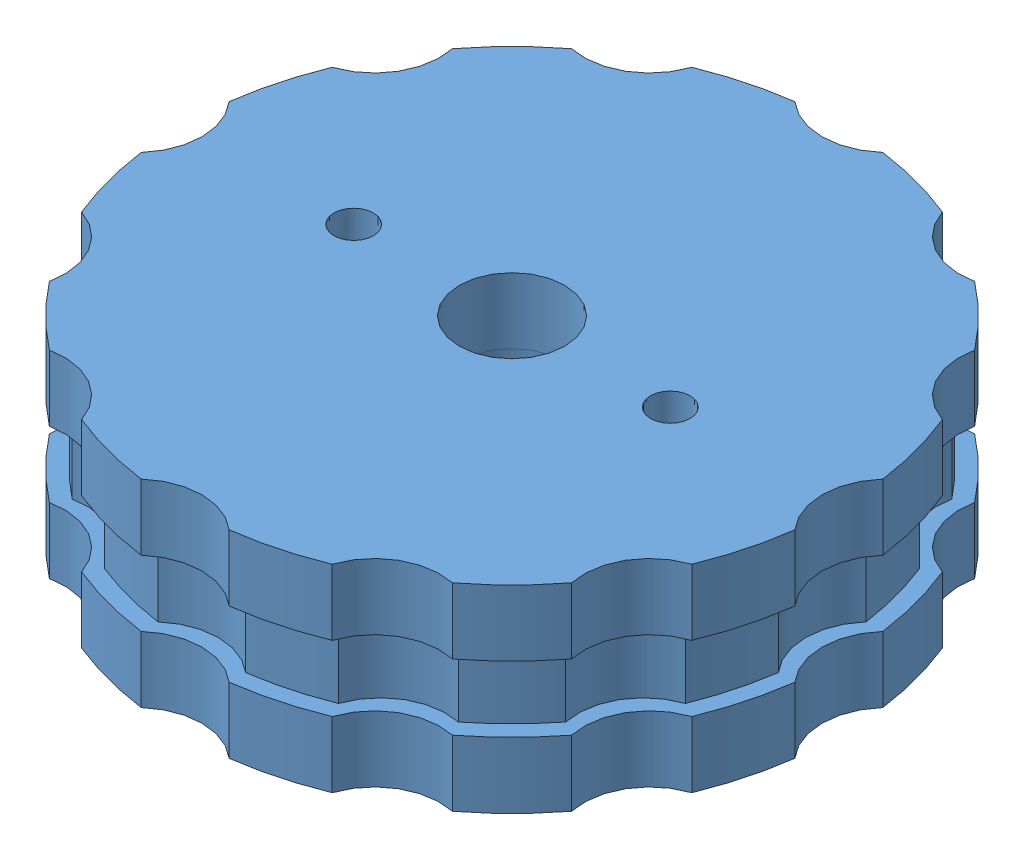
SolidWorks assembly Roller Assembly, configuration Default. Lengths in mm.
Overall size (49.55 15 49.55).
3 component instances, 1 part files, 9 mates.
Components (placement in the parent):
- Roller Section-1: Roller Section [Middle] at origin size (47.03 5 47.03)
- Roller Section-2: Roller Section [Top] at (0 5 0) size (49.55 5 49.55)
- Roller Section-3: Roller Section [Top] at (0 -5 0) size (49.55 5 49.55)
Mates (geometry in assembly coordinates):
- Coincident1: coincident aligned: plane of ? through (7.7282 0 0) normal (0 1 0)
- Concentric1: concentric aligned: cylinder of Roller Section-1 through (7.7282 5 0) axis (0 -1 0) radius 4; cylinder of Roller Section-2 through (7.7282 10 0) axis (0 -1 0) radius 4
- Concentric2: concentric aligned: cylinder of Roller Section-1 through (7.7282 5 0) axis (0 -1 0) radius 4; cylinder of Roller Section-3 through (7.7282 0 0) axis (0 -1 0) radius 4
- Concentric3: concentric aligned: circle of Roller Section-1; circle of Roller Section-3
- Concentric4: concentric aligned: circle of Roller Section-1; circle of Roller Section-2
- Coincident4: coincident anti-aligned: plane of Roller Section-1 through (7.7282 0 0) normal (0 -1 0); plane of Roller Section-3 through (7.7282 0 0) normal (0 1 0)
- Coincident5: coincident anti-aligned: plane of Roller Section-1 through (7.7282 5 0) normal (0 1 0); plane of Roller Section-2 through (7.7282 5 0) normal (0 -1 0)
- Coincident6: coincident aligned: plane of Roller Section-1 through (0 0 0) normal (0 0 1); plane of assembly
- Coincident7: coincident aligned: plane of Roller Section-1 through (0 0 0) normal (1 0 0); plane of assembly
